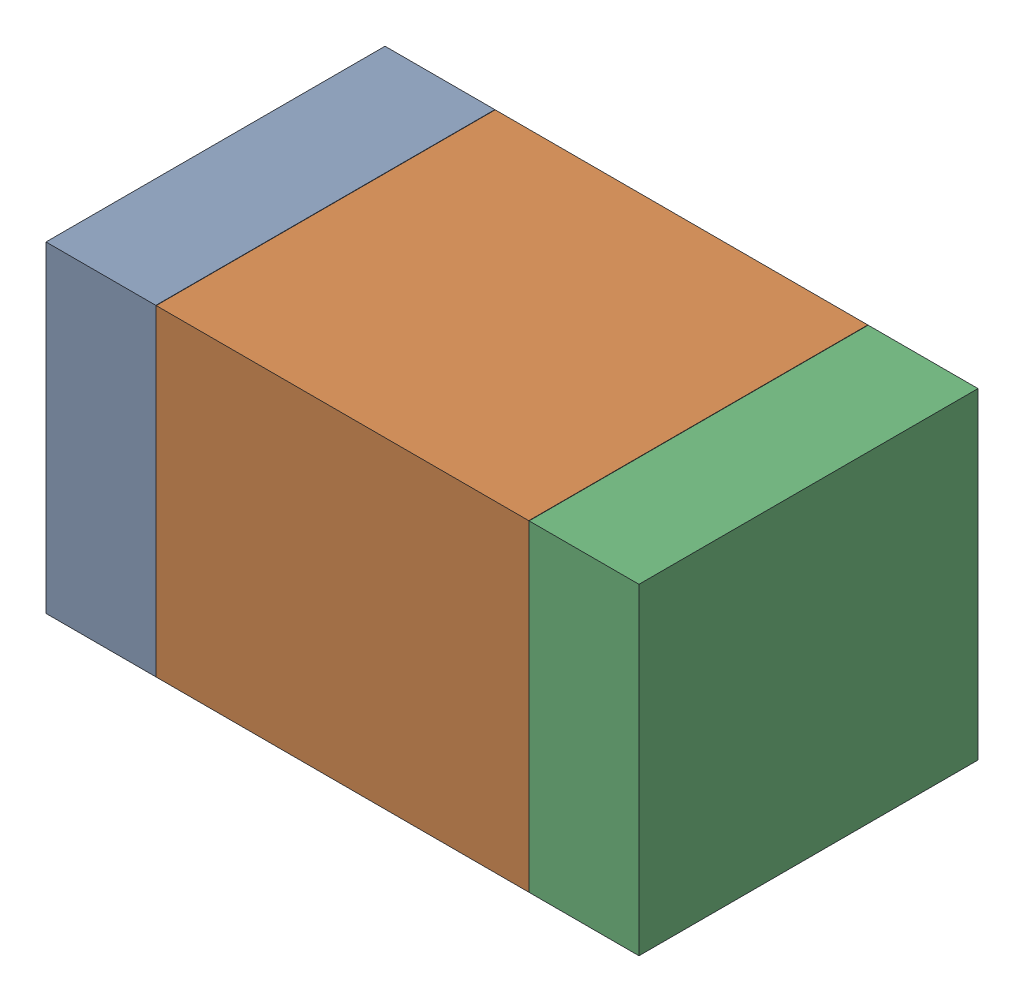
SolidWorks assembly C19, configuration Default. Lengths in mm.
Overall size (1.75 0.95 1).
6 component instances, 2 part files, 0 mates.
Components (placement in the parent):
- 6575498272-1: 6575498272 [Default] at (29.0055 14.605 0) size (0.32 0.95 1)
  - Extruded_8-1: Extruded_8 [Default] at origin size (0.32 0.95 1)
- 6575498112-1: 6575498112 [Default] at (29.718 14.605 0) size (1.1 0.95 1)
  - Extruded_9-1: Extruded_9 [Default] at origin size (1.1 0.95 1)
- 6575498272-2: 6575498272 [Default] at (30.4305 14.605 0) size (0.32 0.95 1)
  - Extruded_8-1: Extruded_8 [Default] at origin size (0.32 0.95 1)
